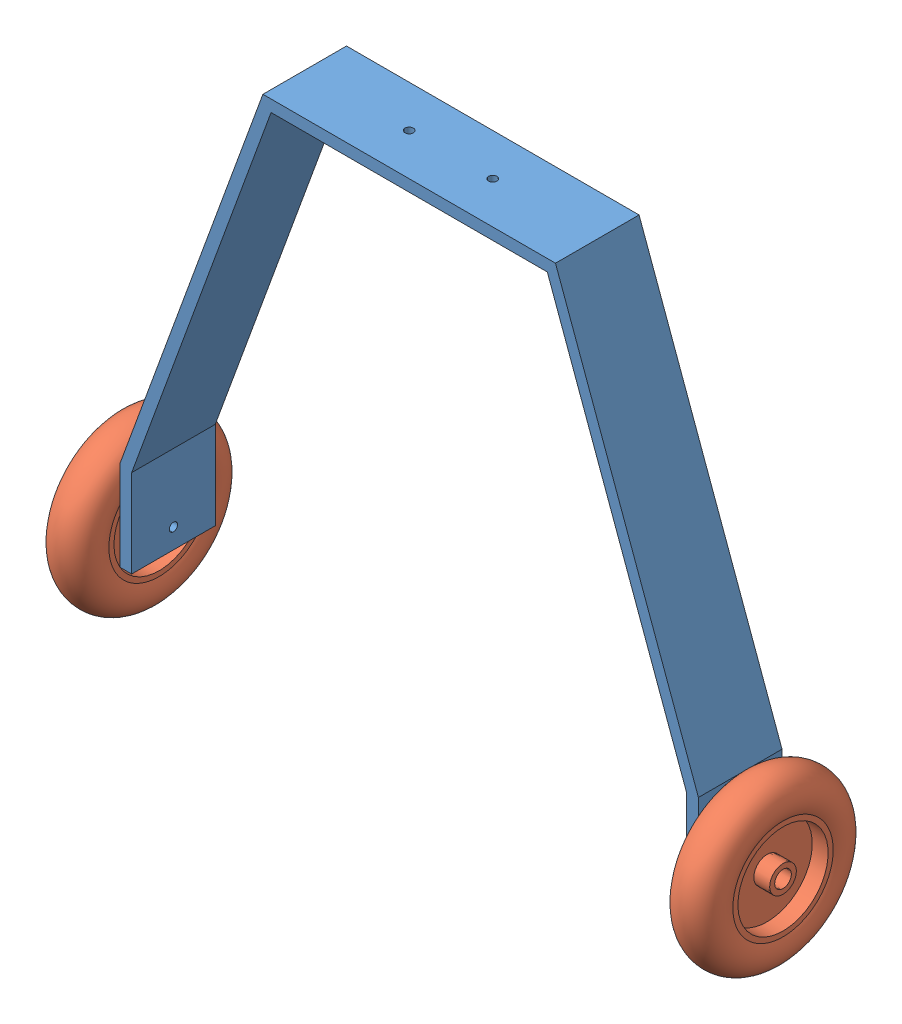
SolidWorks assembly assembly landing gear, configuration Default. Lengths in mm.
Overall size (400.4 343.21 134.64).
3 component instances, 2 part files, 4 mates.
Components (placement in the parent):
- frame-1: frame [Default] at (47.9053 91.8578 -25) size (346 287.76 50)
- wheel-1: wheel [Default] at (-51.1947 -184.0334 0) x (1 0 0) z (0 0.456819 0.88956) size (27.2 100 100)
- wheel-2: wheel [Default] at (322.0053 -184.0334 0) x (1 0 0) z (0 0.456819 0.88956) size (27.2 100 100)
Mates (geometry in assembly coordinates):
- Concentric1: concentric: cylinder of frame-1 through (-37.5947 -184.0334 0) axis (1 0 0) radius 2.5; cylinder of wheel-1 through (-58.2167 -184.0334 0) axis (-1 0 0) radius 5
- Tangent1: tangent anti-aligned: plane of frame-1 through (-37.5947 -142.1422 25) normal (-1 0 0); torus of wheel-1
- Tangent2: tangent: plane of frame-1 through (308.4053 -142.1422 25) normal (1 0 0); torus of wheel-2
- Concentric2: concentric anti-aligned: cylinder of frame-1 through (-37.5947 -184.0334 0) axis (1 0 0) radius 2.5; cylinder of wheel-2 through (314.9833 -184.0334 0) axis (-1 0 0) radius 5
